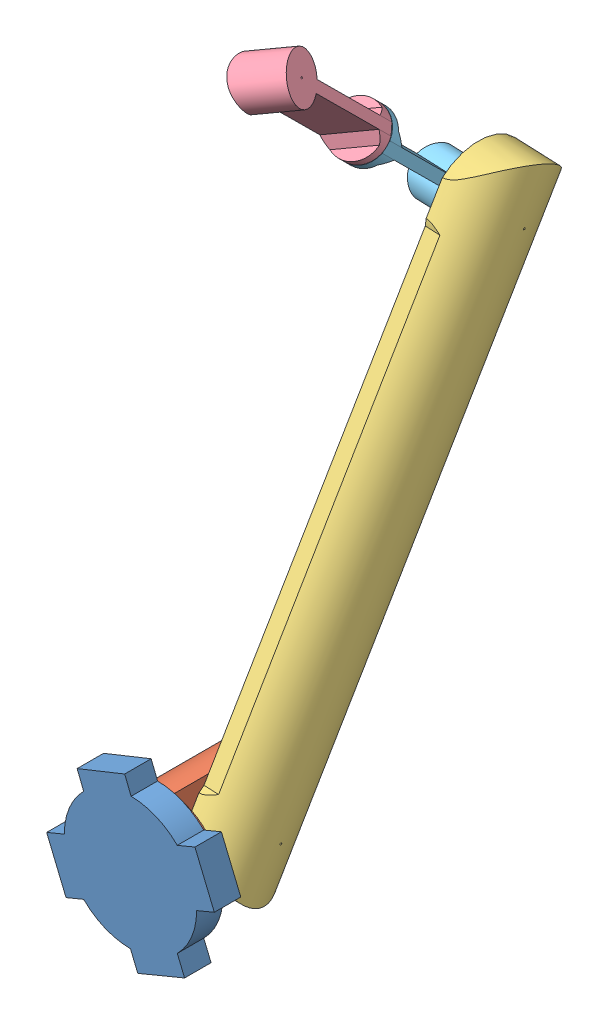
SolidWorks assembly armassembly, configuration Default. Lengths in mm.
Overall size (281.51 851.09 497.26).
6 component instances, 5 part files, 6 mates.
Components (placement in the parent):
- armbase-1: armbase [Default] at (-3.793 12.8281 -1.286) size (190 188.21 30)
- Arm Shoulder-1: Arm Shoulder [Default] at (-3.793 12.8281 -1.786) x (0.043488 0.999054 0) z (0 0 -1) size (110 110 140)
- LowerArm-1: LowerArm [Default] at (21.5741 584.0868 -330.8076) x (0.005445 0.125078 -0.992132) z (0.999054 -0.043488 0) size (429.57 567.65 63.91)
- upperarmassembly-1: upperarmassembly [Default] at (36.1182 631.8279 -173.4999) x (0.452411 -0.853559 0.258383) z (-0.860669 -0.341992 0.377213) size (184.29 333.29 139.75) (flexible)
  - UpperArmtop-1: UpperArmtop [Default] at (-74.0027 148.359 -6.3156) size (111.7 174.07 56.17)
  - UpperArmbottom-1: UpperArmbottom [Default] at (65.6584 -288.4514 -20.5007) x (-0.870339 0.05734 -0.489103) z (-0.489103 -0.216295 0.844982) size (111.7 174.07 56.17)
Mates (geometry in assembly coordinates):
- Concentric1: concentric anti-aligned: cylinder of armbase-1 through (-3.793 12.8281 28.714) axis (0 0 -1) radius 75; cylinder of Arm Shoulder-1 through (-3.793 12.8281 -16.786) axis (0 0 1) radius 55
- Distance1: distance = 0.5 mm anti-aligned: plane of Arm Shoulder-1 through (-3.793 12.8281 -1.786) normal (0 0 1); plane of armbase-1 through (-3.793 12.8281 -1.286) normal (0 0 -1)
- Concentric4: concentric anti-aligned: cylinder of Arm Shoulder-1 through (-58.742 15.2201 -86.786) axis (0.999054 -0.043488 0) radius 1; cylinder of LowerArm-1 through (55.8408 10.2323 -86.786) axis (-0.999054 0.043488 0) radius 1
- Distance4: distance = 0.5 mm anti-aligned: plane of LowerArm-1 through (17.9067 499.8353 -341.4493) normal (-0.999054 0.043488 0); plane of Arm Shoulder-1 through (-3.793 12.8281 -86.786) normal (0.999054 -0.043488 0)
- Concentric5: concentric anti-aligned: cylinder of LowerArm-1 through (72.3571 497.4651 -341.4493) axis (-0.999054 0.043488 0) radius 1; cylinder of upperarmassembly-1/UpperArmbottom-1 through (-37.0433 502.2273 -341.4493) axis (0.999054 -0.043488 0) radius 1
- Distance5: distance = 0.5 mm anti-aligned: plane of upperarmassembly-1/UpperArmbottom-1 through (17.4071 499.8571 -341.4493) normal (0.999054 -0.043488 0); plane of LowerArm-1 through (17.9067 499.8353 -341.4493) normal (-0.999054 0.043488 0)
